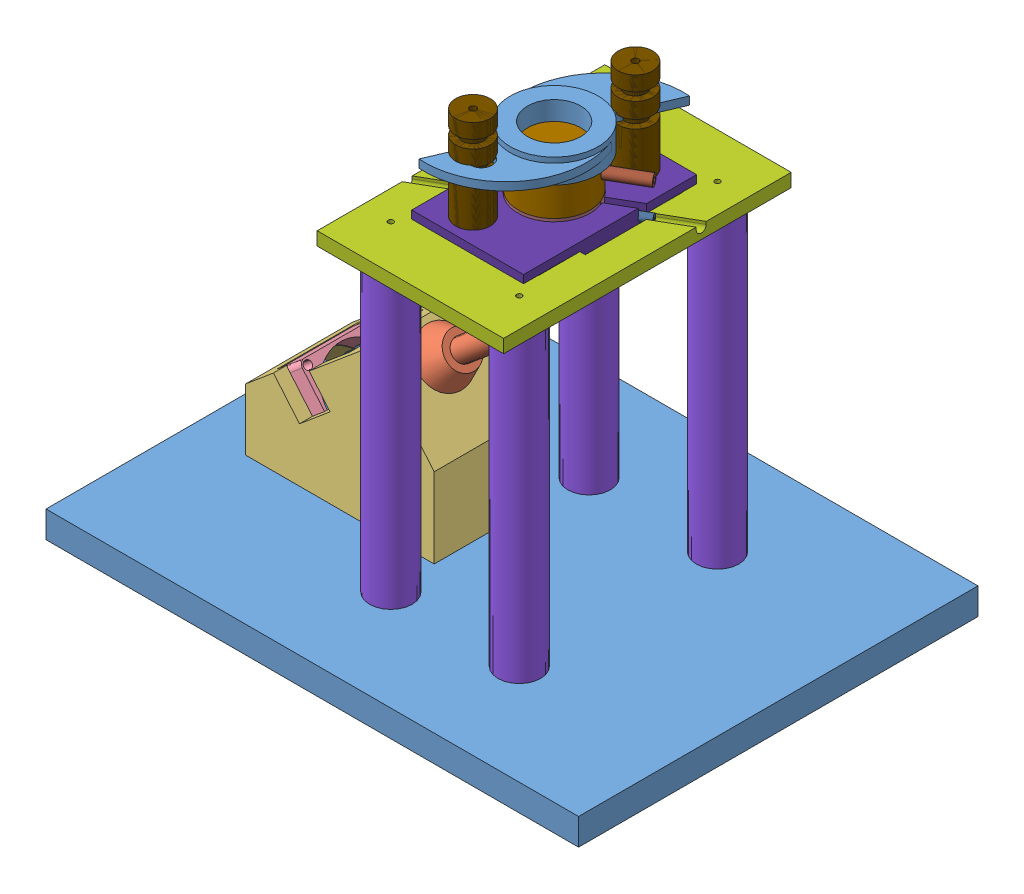
SolidWorks assembly Assembly-CuringBox, configuration Default. Lengths in mm.
Overall size (200 168.46 150).
33 component instances, 19 part files, 8 mates.
Components (placement in the parent):
- Basement-1: Basement [Default] at (-6.4872 -22.7177 0) size (200 10 150)
- Assembly - Light source-1: Assembly - Light source [Default] at (-28.585 77.0082 40.191) x (0.010002 0.008434 0.999914) z (-0.999938 -0.00475 0.010042) size (41.2 115.59 116.94)
  - OpticFiber-1: OpticFiber [Default] at (-40.8101 -52.2302 17.6957) x (0.013083 0.639054 -0.769051) z (0.999911 -0.010395 0.008372) size (91.07 30.56 20)
  - Base-2: Base [Default] at (-61.5131 -88.9411 56.8669) x (0.999914 -0.008385 0.010042) z (-0.010002 0.004835 0.999938) size (40 58.57 70.79)
  - Dissipation fan-1: Dissipation fan [Default] at (-41.3328 -71.7179 41.0224) x (-0.000031 -0.769116 -0.639109) z (0.999914 -0.008385 0.010042) size (30 10 30)
  - LED+heatsink-3: LED+heatsink [Default] at (-41.0378 -63.3498 31.0771) x (0.99983 -0.018335 0.001773) z (0.012967 0.768943 0.639185) size (28 18.4 22)
  - Rubber cone-1: Rubber cone [Default] at (-39.6281 15.8503 -38.4669) x (0.978759 -0.009228 -0.204807) z (0.204841 0.002922 0.978791) size (20.32 10 19.57)
- Assembly-bioreact holder+clamp base+columns-3: Assembly-bioreact holder+clamp base+columns [Default] at (9.4065 135.3806 29.9143) x (0 0 1) z (-1 0 0) size (108 158.46 98.29)
  - Bioreactor holder-1: Bioreactor holder [Default] at (-29.8672 -32.6383 0) size (108 5 70)
  - Column-1: Column [Default] at (-67.0842 -148.0983 24.1221) size (16 118.46 16)
  - Column-2: Column [Default] at (7.3497 -148.0983 24.1221) size (16 118.46 16)
  - Column-3: Column [Default] at (-67.0842 -148.0983 -24.1221) size (16 118.46 16)
  - Column-4: Column [Default] at (7.3497 -148.0983 -24.1221) size (16 118.46 16)
  - mycroscope clamp 3D + LVB1-2: mycroscope clamp 3D + LVB1 [Default] at (-33.3532 27.8985 2.0127) x (0.866025 0 -0.5) z (0.5 0 0.866025) size (77.29 43 68.87)
    - 3D view live box 1-1: 3D view live box 1 [Assemblata] at (6.7199 -46.9356 0) size (27 23 55)
      - 3Dview-Top-1: 3Dview-Top [Default] at (-2.6946 -4.6013 0) size (27 15 55)
        - Top-1: Top [Default] at origin size (27 15 27)
        - 3x1-1: 3x1 [Default] at (0 6.5 7.5) x (0.999962 0.00877 0) z (0 0 1) size (3 3 20)
        - 4x2-1: 4x2 [Default] at (0 8 -27.5) size (4 4 20)
      - 3Dview-Inner bottom-1: 3Dview-Inner bottom [Default] at (-2.6946 -11.6013 0) x (0 0 -1) z (1 0 0) size (55 6.7 21)
        - Inner bottom-1: Inner bottom [Default] at origin size (21 6.7 21)
        - 3x1-2: 3x1 [Default] at (-7.5 2.5 0) x (0 0.981723 0.190315) z (-1 0 0) size (3 3 20)
        - 3x1-4: 3x1 [Default] at (27.5 2.5 0) x (0 -0.991525 0.129918) z (-1 0 0) size (3 3 20)
      - Bottom-1: Bottom [Default] at (-2.6946 -12.6013 0) x (0 0 -1) z (1 0 0) size (27 8 27)
      - Inner up-1: Inner up [Default] at (-2.6946 -6.6013 0) size (21 4.9 21)
      - glass bottom-1: glass bottom [Default] at (-2.6946 -11.6013 0) size (21 0.3 21)
      - Membrane-1: Membrane [Default] at (-2.6946 -6.6013 0) size (19 0.1 19)
    - mycroscope clamp base-1: mycroscope clamp base [Default] at (4.0253 -60.5369 0) x (0.866025 0 0.5) z (-0.5 0 0.866025) size (65 8 42)
    - mycroscope clamp colonna-1: mycroscope clamp colonna [Default] at (-12.1415 -52.5369 -17.9942) size (13 37 13)
    - mycroscope clamp colonna-2: mycroscope clamp colonna [Default] at (20.1921 -52.5369 17.9942) size (13 37 13)
    - mycroscope clamp ali LVB1-2: mycroscope clamp ali LVB1 [Default] at (4.0253 -34.4369 0) x (0.990162 0 0.139923) z (-0.139923 0 0.990162) size (60.98 9.1 54.76)
- mycroscope clamp colonna-1: mycroscope clamp colonna [Default] at (1.9065 110.7423 23.045) size (13 37 13)
- mycroscope clamp colonna-2: mycroscope clamp colonna [Default] at (16.9065 110.7423 -22.9509) size (13 37 13)
Mates (geometry in assembly coordinates):
- Distanza1: distance = 55 mm: line of Basement-1 through (93.5128 -12.7177 -75) axis (-1 0 0); line of Assembly - Light source-1/Base-2 through (-86.4872 -12.7177 -20) axis (1 0 0)
- Coincidente4: coincident anti-aligned: plane of Basement-1 through (-6.4872 -12.7177 0) normal (0 1 0); plane of Assembly - Light source-1/Base-2 through (-85.6336 -12.7177 20) normal (0 -1 0)
- Distanza6: distance = 180 mm: line of Basement-1 through (93.5128 -12.7177 75) axis (0 0 -1); line of Assembly - Light source-1/Base-2 through (-86.4872 -12.7177 20) axis (0 0 -1)
- Concentrico1: concentric aligned: circle of Assembly - Light source-1/Rubber cone-1; circle of ?
- Coincidente5: coincident anti-aligned: plane of Basement-1 through (-6.4872 -12.7177 0) normal (0 1 0); plane of Assembly-bioreact holder+clamp base+columns-3/Column-2 through (-14.7156 -12.7177 37.264) normal (0 -1 0)
- Parallelo1: parallel aligned: line of Basement-1 through (93.5128 -12.7177 75) axis (0 0 -1); line of Assembly-bioreact holder+clamp base+columns-3/Bioreactor holder-1 through (44.4065 107.7423 54.047) axis (0 0 -1)
- Coincidente7: coincident anti-aligned: circle of ?; circle of mycroscope clamp colonna-2
- Coincidente8: coincident anti-aligned: circle of ?; circle of mycroscope clamp colonna-1
